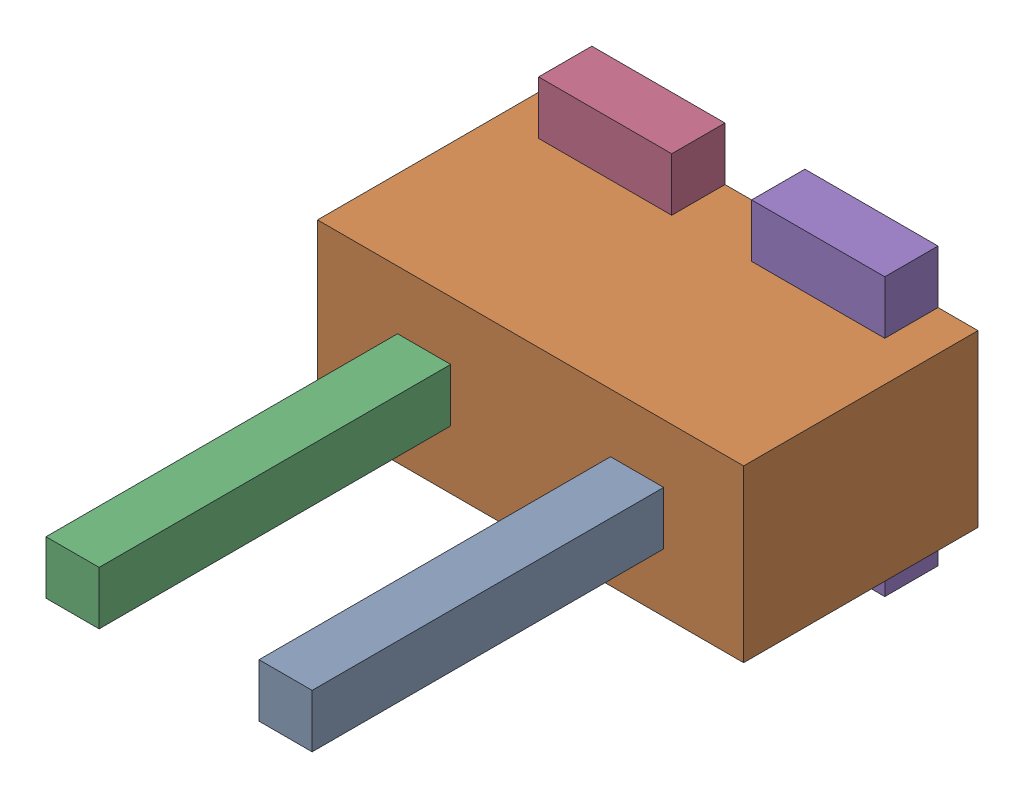
SolidWorks assembly J7, configuration ﾃﾞﾌｫﾙﾄ. Lengths in mm.
Overall size (4 2.6 5.5).
10 component instances, 3 part files, 0 mates.
Components (placement in the parent):
- 689260424-1: 689260424 [ﾃﾞﾌｫﾙﾄ] at (14.6526 8.255 2.2) size (0.5 0.5 3.3)
  - Extruded_23-1: Extruded_23 [ﾃﾞﾌｫﾙﾄ] at origin size (0.5 0.5 3.3)
- 689260560-1: 689260560 [ﾃﾞﾌｫﾙﾄ] at (13.6525 8.255 0) size (4 1.6 2.2)
  - Extruded_24-1: Extruded_24 [ﾃﾞﾌｫﾙﾄ] at origin size (4 1.6 2.2)
- 689260424-2: 689260424 [ﾃﾞﾌｫﾙﾄ] at (12.6531 8.255 2.2) size (0.5 0.5 3.3)
  - Extruded_23-1: Extruded_23 [ﾃﾞﾌｫﾙﾄ] at origin size (0.5 0.5 3.3)
- 689260696-1: 689260696 [ﾃﾞﾌｫﾙﾄ] at (12.6526 8.2551 0) size (1.25 2.6 0.5)
  - Extruded_25-1: Extruded_25 [ﾃﾞﾌｫﾙﾄ] at origin size (1.25 2.6 0.5)
- 689260696-2: 689260696 [ﾃﾞﾌｫﾙﾄ] at (14.6526 8.2551 0) size (1.25 2.6 0.5)
  - Extruded_25-1: Extruded_25 [ﾃﾞﾌｫﾙﾄ] at origin size (1.25 2.6 0.5)
